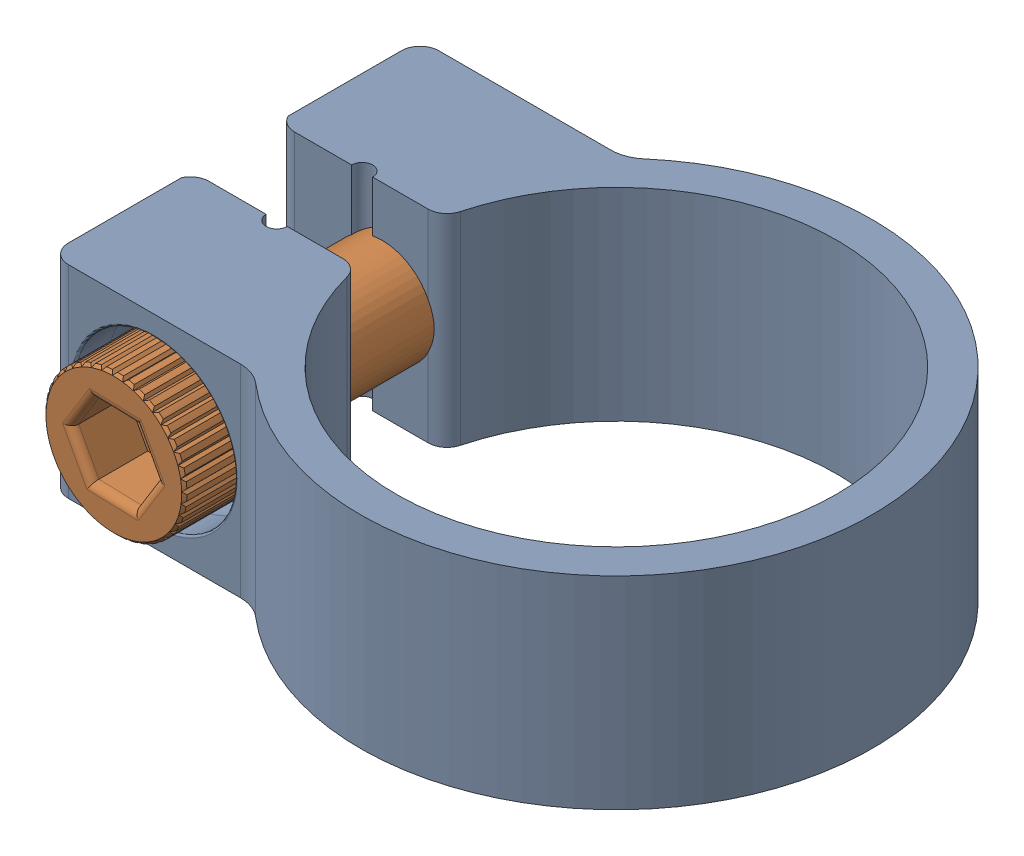
SolidWorks assembly Assem_HClamp, configuration Default. Lengths in mm.
Overall size (43.17 13.72 34.65).
2 component instances, 2 part files, 2 mates.
Components (placement in the parent):
- HClamp_Collar-1: HClamp_Collar [Default] x (1 0 0) z (0 1 0) size (43.17 34.65 13.72)
- HClamp_Screw-1: HClamp_Screw [Default] at (-12.3336 6.858 -10.8204) x (0.880478 0.474086 0) z (0.474086 -0.880478 0) size (9.55 26.11 9.54)
Mates (geometry in assembly coordinates):
- Concentric2: concentric: cylinder of HClamp_Collar-1 through (-12.3336 6.858 -17.3263) axis (0 0 1) radius 2.921; cylinder of HClamp_Screw-1 through (-12.3336 6.858 1.3116) axis (0 0 -1) radius 2.794
- Coincident3: coincident anti-aligned: plane of HClamp_Collar-1 through (-12.3336 6.858 8.9408) normal (0 0 1); plane of HClamp_Screw-1 through (-8.1291 9.1219 8.9408) normal (0 0 -1)
